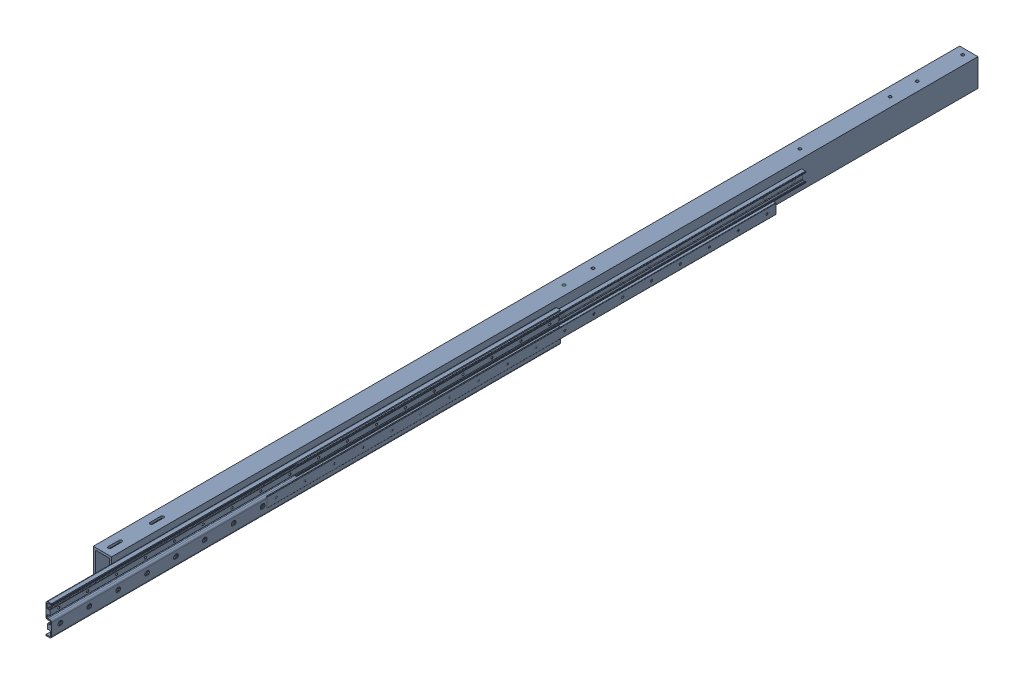
SolidWorks assembly Mirrorbeam+slider-left, configuration Default. Lengths in mm.
Overall size (66.8 93.8 3265.2).
5 component instances, 4 part files, 2 mates.
Components (placement in the parent):
- beam-1: beam [Default] at (-0.0019 0 0) x (-1 0 0) z (0 0 -1) size (50.8 76.2 2400)
- MirrorDSD28-1410-2-1: MirrorDSD28-1410-2 [Default] at (32.9 -13.7009 -544.8) x (0 0 1) z (0 1 0) size (1410 17 84)
  - ROLLCO-DS28-BRAKET2X-ASN28-Slider-1: ROLLCO-DS28-BRAKET2X-ASN28-Slider [Default] at (-683 0.5 -3.836) size (1410 15 84)
  - ROLLCO-ASN28-Rail-1: ROLLCO-ASN28-Rail [Default] at (-1280.1362 0 -35) size (1410 12.25 28)
  - ROLLCO-ASN28-Rail_2-1: ROLLCO-ASN28-Rail_2 [Default] at (-1366 1 31.2009) size (1410 12.25 28)
Mates (geometry in assembly coordinates):
- Concentric1: concentric aligned: circle of beam-1; circle of MirrorDSD28-1410-2-1/ROLLCO-ASN28-Rail_2-1
- Parallel1: parallel anti-aligned: plane of beam-1 through (-25.4019 38.1 -2400) normal (0 1 0); plane of MirrorDSD28-1410-2-1/ROLLCO-DS28-BRAKET2X-ASN28-Slider-1 through (33.4 -59.537 -1227.8) normal (0 -1 0)
